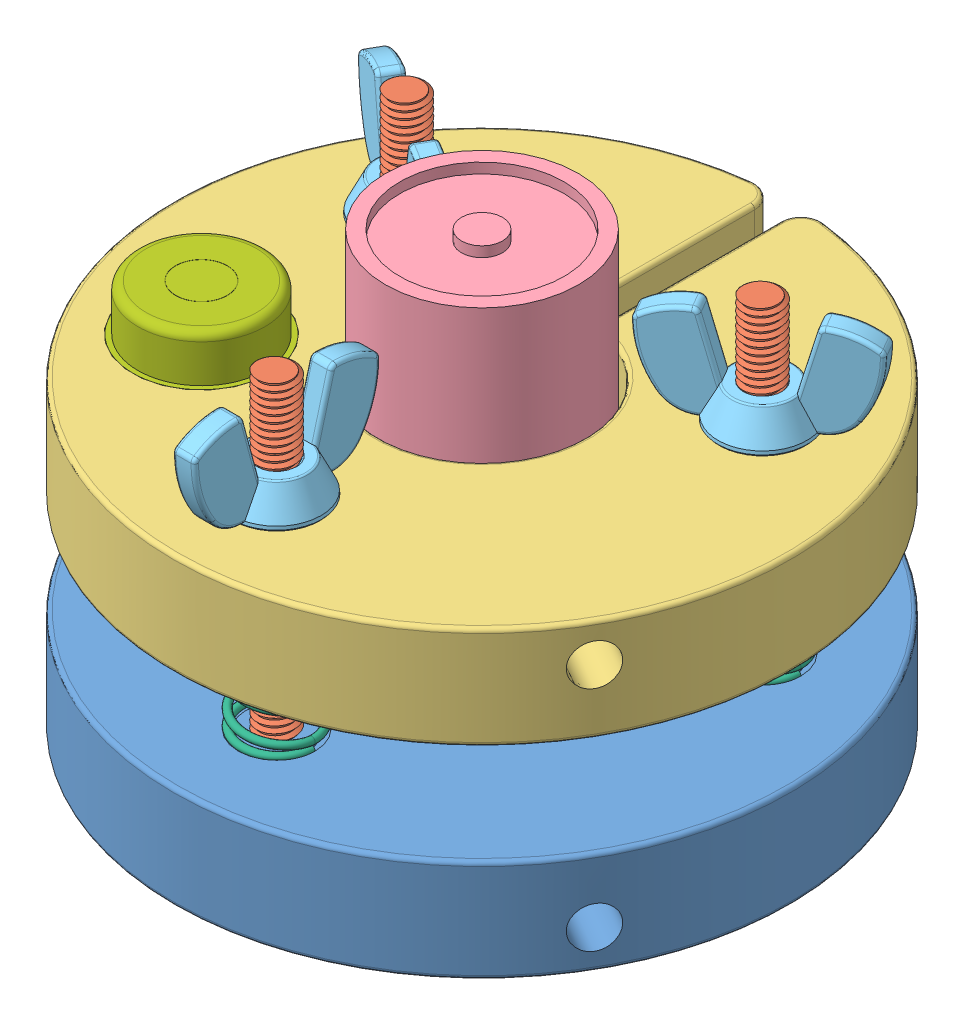
SolidWorks assembly base_assy 0.375 Spring, configuration 0.375 OD Spring. Lengths in mm.
Overall size (76.2 54.15 76.2).
13 component instances, 7 part files, 39 mates.
Components (placement in the parent):
- base_bottom-1: base_bottom [Default] at origin size (76.2 12.7 76.2)
- 95475A509 Rod-6: 95475A509 Rod [Default] at (0 25.7175 25.4) size (5.46 52.36 4.85)
- 95475A509 Rod-7: 95475A509 Rod [Default] at (21.997 25.7175 -12.7) size (5.46 52.36 4.85)
- 95475A509 Rod-8: 95475A509 Rod [Default] at (-21.997 25.7175 -12.7) size (5.46 52.36 4.85)
- base_top-1: base_top [Default] at (0 24.9555 0) x (-1 0 0) z (0 0 -1) size (76.2 12.7 76.2)
- Li200-1: Li200 [Default] at (0 28.1305 0) x (-1 0 0) z (0 0 -1) size (23.88 25.4 50.04)
- 90866A111 Wingnut-1: 90866A111 Wingnut [90866A111] at (0 37.6555 25.4) x (0 0 -1) z (0 -1 0) size (23.02 11.07 12.22)
- 90866A111 Wingnut-2: 90866A111 Wingnut [90866A111] at (21.997 37.6555 -12.7) x (-0.866025 0 0.5) z (0 -1 0) size (23.02 11.07 12.22)
- 90866A111 Wingnut-3: 90866A111 Wingnut [90866A111] at (-21.997 37.6555 -12.7) x (0.866025 0 0.5) z (0 -1 0) size (23.02 11.07 12.22)
- 9657K276 Spring-1: 9657K276 Spring [9657K276] at (0 12.7 25.4) x (1 0 0) z (0 -1 0) size (9.8 9.93 13.15)
- 9657K276 Spring-2: 9657K276 Spring [9657K276] at (21.997 12.7 -12.7) x (1 0 0) z (0 -1 0) size (9.8 9.93 13.15)
- 9657K276 Spring-3: 9657K276 Spring [9657K276] at (-21.997 12.7 -12.7) x (1 0 0) z (0 -1 0) size (9.8 9.93 13.15)
- 2147A610 Plastic Level-1: 2147A610 Plastic Level [2147A61] at (-21.997 35.1155 12.7) x (-1 0 0) z (0 0 -1) size (16.89 8.26 16.89)
Mates (geometry in assembly coordinates):
- Coincident1: coincident: plane of base_bottom-1 through (0 0 0) normal (0 0 1); plane of assembly through (0 0 0) normal (0 0 1)
- Coincident2: coincident: plane of base_bottom-1 through (0 0 0) normal (0 1 0); plane of assembly through (0 0 0) normal (0 1 0)
- Coincident3: coincident aligned: plane of base_bottom-1 through (0 0 0) normal (1 0 0); plane of assembly through (0 0 0) normal (1 0 0)
- Coincident8: coincident anti-aligned: plane of 95475A509 Rod-6 through (0 0 25.4) normal (0 -1 0); plane of assembly through (0 0 0) normal (0 1 0)
- Coincident9: coincident anti-aligned: plane of 95475A509 Rod-7 through (21.997 0 -12.7) normal (0 -1 0); plane of assembly through (0 0 0) normal (0 1 0)
- Coincident10: coincident anti-aligned: plane of 95475A509 Rod-8 through (-21.997 0 -12.7) normal (0 -1 0); plane of assembly through (0 0 0) normal (0 1 0)
- Concentric1: concentric anti-aligned: circle of base_bottom-1; circle of 95475A509 Rod-6
- Parallel1: parallel aligned: plane of 95475A509 Rod-6 through (0 25.7175 25.4) normal (0 0 1); plane of assembly through (0 0 0) normal (0 0 1)
- Concentric2: concentric anti-aligned: circle of base_bottom-1; circle of 95475A509 Rod-7
- Concentric3: concentric anti-aligned: circle of base_bottom-1; circle of 95475A509 Rod-8
- Parallel2: parallel aligned: plane of 95475A509 Rod-7 through (21.997 25.7175 -12.7) normal (0 0 1); plane of assembly through (0 0 0) normal (0 0 1)
- Parallel3: parallel aligned: plane of 95475A509 Rod-8 through (-21.997 25.7175 -12.7) normal (0 0 1); plane of assembly through (0 0 0) normal (0 0 1)
- Concentric4: concentric aligned: circle of 95475A509 Rod-6; circle of base_top-1
- Concentric5: concentric aligned: circle of 95475A509 Rod-8; circle of base_top-1
- Coincident26: coincident anti-aligned: plane of base_top-1 through (83.9614 28.1305 0) normal (0 1 0); plane of Li200-1 through (0 28.1305 0) normal (0 -1 0)
- Coincident27: coincident anti-aligned: plane of Li200-1 through (0 28.1305 0) normal (-1 0 0); plane of assembly through (0 0 0) normal (1 0 0)
- Coincident28: coincident anti-aligned: plane of base_top-1 through (0 37.6555 0) normal (0 1 0); plane of 90866A111 Wingnut-1 through (0 37.6555 25.4) normal (0 -1 0)
- Coincident29: coincident anti-aligned: plane of base_top-1 through (0 37.6555 0) normal (0 1 0); plane of 90866A111 Wingnut-2 through (21.997 37.6555 -12.7) normal (0 -1 0)
- Coincident30: coincident anti-aligned: plane of base_top-1 through (0 37.6555 0) normal (0 1 0); plane of 90866A111 Wingnut-3 through (-21.997 37.6555 -12.7) normal (0 -1 0)
- Concentric10: concentric anti-aligned: circle of 95475A509 Rod-7; circle of 90866A111 Wingnut-2
- Concentric11: concentric anti-aligned: circle of 95475A509 Rod-8; circle of 90866A111 Wingnut-3
- Concentric12: concentric anti-aligned: circle of 95475A509 Rod-6; circle of 90866A111 Wingnut-1
- Coincident31: coincident aligned: plane of 95475A509 Rod-6 through (0 25.7175 25.4) normal (1 0 0); plane of 90866A111 Wingnut-1
- Angle1: planar angle = 2.094395 rad aligned: plane of 95475A509 Rod-7 through (21.997 25.7175 -12.7) normal (1 0 0); plane of 90866A111 Wingnut-2
- Angle2: planar angle = 2.094395 rad aligned: plane of 90866A111 Wingnut-3; plane of 95475A509 Rod-8 through (-21.997 25.7175 -12.7) normal (1 0 0)
- Coincident32: coincident anti-aligned: plane of Li200-1 through (0 28.1305 0) normal (0 0 -1); plane of assembly through (0 0 0) normal (0 0 1)
- Coincident33: coincident anti-aligned: plane of base_bottom-1 through (0 12.7 0) normal (0 1 0); plane of 9657K276 Spring-3 through (-21.997 12.7 -12.7) normal (0 -1 0)
- Coincident34: coincident anti-aligned: plane of base_bottom-1 through (0 12.7 0) normal (0 1 0); plane of 9657K276 Spring-2 through (21.997 12.7 -12.7) normal (0 -1 0)
- Coincident35: coincident anti-aligned: plane of base_bottom-1 through (0 12.7 0) normal (0 1 0); plane of 9657K276 Spring-1 through (0 12.7 25.4) normal (0 -1 0)
- Coincident36: coincident aligned: plane of 95475A509 Rod-6 through (0 25.7175 25.4) normal (0 0 1); plane of 9657K276 Spring-1 through (0 12.7 25.4) normal (0 0 1)
- Coincident37: coincident aligned: plane of 95475A509 Rod-6 through (0 25.7175 25.4) normal (1 0 0); plane of 9657K276 Spring-1
- Coincident38: coincident aligned: plane of 95475A509 Rod-7 through (21.997 25.7175 -12.7) normal (1 0 0); plane of 9657K276 Spring-2
- Coincident39: coincident aligned: plane of 95475A509 Rod-7 through (21.997 25.7175 -12.7) normal (0 0 1); plane of 9657K276 Spring-2 through (21.997 12.7 -12.7) normal (0 0 1)
- Coincident41: coincident aligned: plane of 95475A509 Rod-8 through (-21.997 25.7175 -12.7) normal (0 0 1); plane of 9657K276 Spring-3 through (-21.997 12.7 -12.7) normal (0 0 1)
- Coincident42: coincident aligned: plane of 95475A509 Rod-8 through (-21.997 25.7175 -12.7) normal (1 0 0); plane of 9657K276 Spring-3
- Coincident44: coincident anti-aligned: plane of base_top-1 through (21.997 25.4 -12.7) normal (0 -1 0); plane of 9657K276 Spring-2 through (21.997 25.4 -12.7) normal (0 1 0)
- Concentric13: concentric aligned: circle of base_top-1; circle of 2147A610 Plastic Level-1
- Coincident45: coincident anti-aligned: plane of base_top-1 through (0 35.1155 0) normal (0 1 0); plane of 2147A610 Plastic Level-1 through (-21.997 35.1155 12.7) normal (0 -1 0)
- Parallel5: parallel anti-aligned: plane of 2147A610 Plastic Level-1 through (-21.997 35.1155 12.7) normal (0 0 -1); plane of assembly through (0 0 0) normal (0 0 1)
